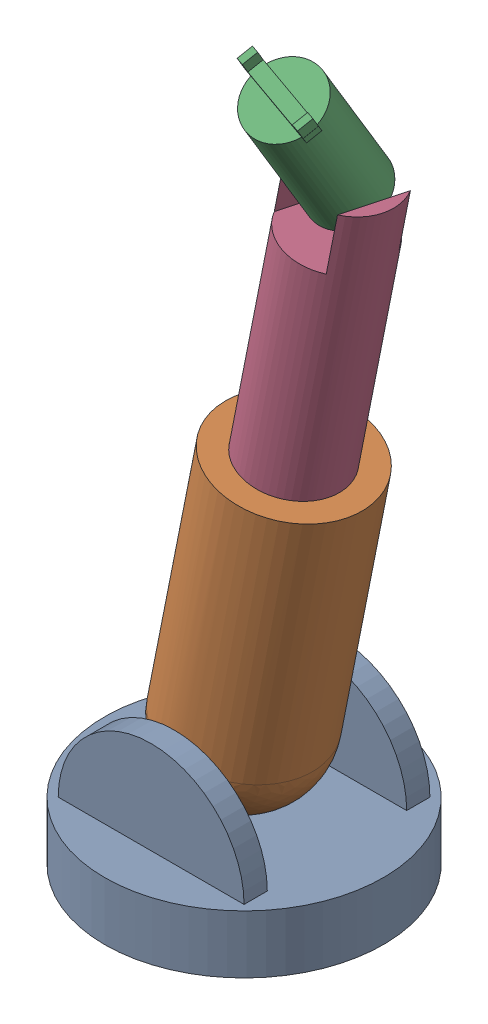
SolidWorks assembly Assem3, configuration Default. Lengths in mm.
Overall size (128.09 340.25 120).
4 component instances, 4 part files, 3 mates.
Components (placement in the parent):
- De-2: De [Default] at (-13.3496 15.4084 132.7878) size (120 65 120)
- khau_1-2: khau_1 [Default] at (8.0465 178.3074 132.7878) x (0 0 -1) z (-0.980901 0.19451 0) size (70 140 60)
- khau_3-3: khau_3 [Default] at (30.29 288.9941 131.4637) x (-0.958336 0.190036 -0.213259) z (0.281226 0.496897 -0.820978) size (35 66 30)
- khau_2-3: khau_2 [Default] at (-11.4045 80.2174 132.7878) x (0.958336 -0.190036 0.213259) z (-0.209186 0.041481 0.976996) size (40 220 40)
Mates (geometry in assembly coordinates):
- Coincident5: coincident anti-aligned: circle of De-2; circle of khau_1-2
- Coincident12: coincident aligned: circle of khau_1-2; circle of khau_2-3
- Coincident13: coincident anti-aligned: circle of khau_3-3; circle of khau_2-3
